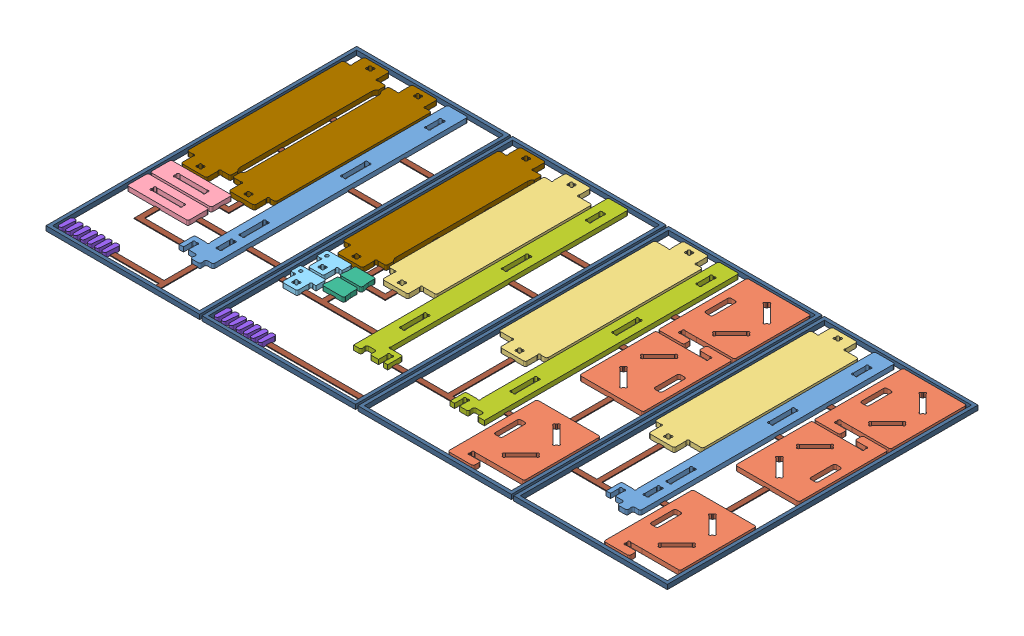
SolidWorks assembly growall_nest, configuration Défaut. Lengths in mm.
Overall size (2440 18 1220).
38 component instances, 11 part files, 87 mates.
Components (placement in the parent):
- post-2: post [Default] at (458.9899 18 -198) x (-1 0 0) z (0 -1 0) size (134 1025 18)
- shelf_side-1: shelf_side [Défaut] at (2418 0 -889) x (0 0 1) z (0 1 0) size (350 250 18)
- beam-1: beam [Défaut] at (1404.4949 0 -1198) x (-1 0 0) z (0 1 0) size (187.99 720 18)
- connector2-1: connector2 [Default] at (22 0 -469) x (0 0 1) z (0 1 0) size (82 240 18)
- connector3-1: connector3 [Défaut] at (654.25 0 -375) x (1 0 0) z (0 1 0) size (100 94 18)
- connector4-1: connector4 [Default] at (746.1933 0 -469) x (0 0 1) z (0 1 0) size (60 86.01 18)
- post2-1: post2 [Default] at (1009.7399 0 -198) x (1 0 0) z (0 1 0) size (134 1000 18)
- pin-16: pin [Défaut] at (29.8913 0 -29.8913) x (1 0 0) z (0 1 0) size (19.55 57.89 18)
- shelf_side-10: shelf_side [Défaut] at (1555.75 0 -848) x (0 0 -1) z (0 1 0) size (350 250 18)
- post2-2: post2 [Default] at (1523.4949 18 -198) x (-1 0 0) z (0 -1 0) size (134 1000 18)
- post-8: post [Default] at (2135.7449 18 -198) x (-1 0 0) z (0 -1 0) size (134 1025 18)
- connector2-2: connector2 [Default] at (22 0 -378) x (0 0 1) z (0 1 0) size (82 240 18)
- connector4-2: connector4 [Default] at (746.1933 0 -400) x (0 0 1) z (0 1 0) size (60 86.01 18)
- connector3-2: connector3 [Défaut] at (654.25 0 -272) x (1 0 0) z (0 1 0) size (100 94 18)
- shelf_side-11: shelf_side [Défaut] at (1555.75 0 -22) x (0 0 -1) z (0 1 0) size (350 250 18)
- shelf_side-12: shelf_side [Défaut] at (1805.75 0 -889) x (0 0 1) z (0 1 0) size (350 250 18)
- shelf_side-14: shelf_side [Défaut] at (2168 0 -22) x (0 0 -1) z (0 1 0) size (350 250 18)
- shelf_side-15: shelf_side [Défaut] at (2168 0 -848) x (0 0 -1) z (0 1 0) size (350 250 18)
- beam-4: beam [Défaut] at (1888.75 0 -478) x (1 0 0) z (0 1 0) size (187.99 720 18)
- beam2-3: beam2 [Défaut] at (239.9899 0 -478) x (1 0 0) z (0 1 0) size (169.49 720 18)
- beam2-4: beam2 [Défaut] at (152 0 -1198) x (-1 0 0) z (0 1 0) size (169.49 720 18)
- beam2-5: beam2 [Défaut] at (764.25 0 -1198) x (-1 0 0) z (0 1 0) size (169.49 720 18)
- layout-1: layout [Default] at origin size (2440 18 1220)
- pin-44: pin [Défaut] at (58.4394 0 -29.8913) x (1 0 0) z (0 1 0) size (19.55 57.89 18)
- pin-46: pin [Défaut] at (86.9874 0 -29.8913) x (1 0 0) z (0 1 0) size (19.55 57.89 18)
- pin-48: pin [Défaut] at (115.5355 0 -29.8913) x (1 0 0) z (0 1 0) size (19.55 57.89 18)
- pin-50: pin [Défaut] at (144.0835 0 -29.8913) x (1 0 0) z (0 1 0) size (19.55 57.89 18)
- pin-52: pin [Défaut] at (172.6316 0 -29.8913) x (1 0 0) z (0 1 0) size (19.55 57.89 18)
- pin-54: pin [Défaut] at (201.1797 0 -29.8913) x (1 0 0) z (0 1 0) size (19.55 57.89 18)
- beam-5: beam [Défaut] at (842.7449 0 -478) x (1 0 0) z (0 1 0) size (187.99 720 18)
- pin-55: pin [Défaut] at (642.1413 0 -29.8913) x (1 0 0) z (0 1 0) size (19.55 57.89 18)
- pin-56: pin [Défaut] at (670.6894 0 -29.8913) x (1 0 0) z (0 1 0) size (19.55 57.89 18)
- pin-57: pin [Défaut] at (699.2374 0 -29.8913) x (1 0 0) z (0 1 0) size (19.55 57.89 18)
- pin-58: pin [Défaut] at (727.7855 0 -29.8913) x (1 0 0) z (0 1 0) size (19.55 57.89 18)
- pin-59: pin [Défaut] at (756.3335 0 -29.8913) x (1 0 0) z (0 1 0) size (19.55 57.89 18)
- pin-60: pin [Défaut] at (784.8816 0 -29.8913) x (1 0 0) z (0 1 0) size (19.55 57.89 18)
- pin-61: pin [Défaut] at (813.4297 0 -29.8913) x (1 0 0) z (0 1 0) size (19.55 57.89 18)
- Tabs^growall_nest-1: Tabs^growall_nest [Défaut] at origin size (2414 3 1194) (virtual)
Mates (geometry in assembly coordinates):
- Coincident2: coordinate: point of ?
- Coincident3: coincident anti-aligned: plane of ? through (863.6224 0 -518.7909) normal (0 -1 0); plane of assembly through (0 0 0) normal (0 1 0)
- Coincident4: coincident anti-aligned: plane of beam2-3 through (244.9899 0 -523.2544) normal (0 -1 0); plane of assembly through (0 0 0) normal (0 1 0)
- Coincident5: coincident anti-aligned: plane of beam2-4 through (147 0 -1152.7456) normal (0 -1 0); plane of assembly through (0 0 0) normal (0 1 0)
- Coincident6: coincident anti-aligned: plane of beam2-5 through (759.25 0 -1152.7456) normal (0 -1 0); plane of assembly through (0 0 0) normal (0 1 0)
- Coincident7: coincident anti-aligned: plane of ? through (986.3675 0 -211) normal (0 -1 0); plane of assembly through (0 0 0) normal (0 1 0)
- Coincident8: coincident anti-aligned: plane of shelf_side-15 through (2168 0 -848) normal (0 -1 0); plane of assembly through (0 0 0) normal (0 1 0)
- Coincident9: coincident anti-aligned: plane of shelf_side-14 through (2168 0 -22) normal (0 -1 0); plane of assembly through (0 0 0) normal (0 1 0)
- Coincident10: coincident anti-aligned: plane of shelf_side-1 through (2418 0 -889) normal (0 -1 0); plane of assembly through (0 0 0) normal (0 1 0)
- Coincident11: coincident anti-aligned: plane of connector2-1 through (22 0 -469) normal (0 -1 0); plane of assembly through (0 0 0) normal (0 1 0)
- Coincident12: coincident anti-aligned: plane of connector4-1 through (746.1933 0 -469) normal (0 -1 0); plane of assembly through (0 0 0) normal (0 1 0)
- Coincident13: coincident anti-aligned: plane of connector3-1 through (656.75 0 -421.0122) normal (0 -1 0); plane of assembly through (0 0 0) normal (0 1 0)
- Coincident15: coincident aligned: plane of ? through (642.6717 0 233.5068) normal (0 1 0); plane of assembly through (0 0 0) normal (0 1 0)
- Coincident16: coincident anti-aligned: plane of post2-2 through (1448.4949 0 -266.7456) normal (0 -1 0); plane of assembly through (0 0 0) normal (0 1 0)
- Coincident17: coincident anti-aligned: plane of post-2 through (371.0021 0 -255.5) normal (0 -1 0); plane of assembly through (0 0 0) normal (0 1 0)
- Coincident18: coincident anti-aligned: plane of post2-1 through (1084.7399 0 -266.7456) normal (0 -1 0); plane of assembly through (0 0 0) normal (0 1 0)
- Coincident21: coincident aligned: plane of ? through (760.5544 0 227.5394) normal (0 1 0); plane of assembly through (0 0 0) normal (0 1 0)
- Coincident27: coincident anti-aligned: plane of ? through (1131.9971 0 248.5286) normal (0 -1 0); plane of assembly through (0 0 0) normal (0 1 0)
- Coincident28: coincident aligned: plane of ? through (572.6518 0 201.4453) normal (0 1 0); plane of assembly through (0 0 0) normal (0 1 0)
- Coincident29: coincident anti-aligned: plane of pin-16 through (29.8913 0 -29.8913) normal (0 -1 0); plane of assembly through (0 0 0) normal (0 1 0)
- Coincident30: coincident anti-aligned: plane of beam-4 through (1891.25 0 -524.0122) normal (0 -1 0); plane of assembly through (0 0 0) normal (0 1 0)
- Coincident31: coincident anti-aligned: plane of ? through (56.6175 0 980.4111) normal (0 -1 0); plane of assembly through (0 0 0) normal (0 1 0)
- Coincident32: coincident anti-aligned: plane of ? through (542.205 0 351.5889) normal (0 -1 0); plane of assembly through (0 0 0) normal (0 1 0)
- Coincident33: coincident anti-aligned: plane of beam-1 through (1401.9949 0 -1151.9878) normal (0 -1 0); plane of assembly through (0 0 0) normal (0 1 0)
- Coincident34: coincident anti-aligned: plane of shelf_side-10 through (1555.75 0 -848) normal (0 -1 0); plane of assembly through (0 0 0) normal (0 1 0)
- Coincident35: coincident anti-aligned: plane of shelf_side-11 through (1555.75 0 -22) normal (0 -1 0); plane of assembly through (0 0 0) normal (0 1 0)
- Coincident36: coincident anti-aligned: plane of shelf_side-12 through (1805.75 0 -889) normal (0 -1 0); plane of assembly through (0 0 0) normal (0 1 0)
- Coincident37: coincident anti-aligned: plane of ? through (224.8375 0 1224) normal (0 -1 0); plane of assembly through (0 0 0) normal (0 1 0)
- Coincident38: coincident anti-aligned: plane of connector3-2 through (656.75 0 -318.0122) normal (0 -1 0); plane of assembly through (0 0 0) normal (0 1 0)
- Coincident39: coincident anti-aligned: plane of connector2-2 through (22 0 -378) normal (0 -1 0); plane of assembly through (0 0 0) normal (0 1 0)
- Coincident40: coincident anti-aligned: plane of connector4-2 through (746.1933 0 -400) normal (0 -1 0); plane of assembly through (0 0 0) normal (0 1 0)
- Coincident42: coincident aligned: line of beam2-4 through (22 0 -1137) axis (0 0 1); line of layout-1 through (22 0 -1198) axis (0 0 1)
- Coincident43: coincident anti-aligned: line of beam2-4 through (145 0 -1198) axis (-1 0 0); line of layout-1 through (22 0 -1198) axis (1 0 0)
- Coincident50: coincident aligned: line of connector2-1 through (22 0 -462) axis (0 0 1); line of layout-1 through (22 0 -1198) axis (0 0 1)
- Coincident53: coincident aligned: line of connector2-2 through (22 0 -371) axis (0 0 1); line of layout-1 through (22 0 -1198) axis (0 0 1)
- Coincident58: coincident aligned: line of pin-16 through (22 0 -72.8913) axis (0 0 1); line of layout-1 through (22 0 -1198) axis (0 0 1)
- Coincident60: coincident aligned: line of beam2-5 through (634.25 0 -1137) axis (0 0 1); line of layout-1 through (634.25 0 -1198) axis (0 0 1)
- Coincident61: coincident anti-aligned: line of beam2-5 through (757.25 0 -1198) axis (-1 0 0); line of layout-1 through (634.25 0 -1198) axis (1 0 0)
- Coincident68: coincident aligned: line of ? through (636.3675 0 -454) axis (0 0 1); line of layout-1 through (636.3675 0 -1194) axis (0 0 1)
- Distance12: distance = 13 mm anti-aligned: plane of ? through (636.3675 18 -461) normal (0 0 -1); plane of beam2-5 through (766.3675 18 -474) normal (0 0 1)
- Coincident70: coincident aligned: line of connector3-2 through (634.25 0 -359) axis (0 0 1); line of layout-1 through (634.25 0 -1198) axis (0 0 1)
- Distance13: distance: line of connector4-2 through (743.25 0 -347.9251) axis (0 1 0); plane of connector3-2 through (734.25 18 -366) normal (1 0 0)
- Coincident74: coincident anti-aligned: line of beam-1 through (1246.5 0 -1137) axis (0 0 1); line of layout-1 through (1246.5 0 -22) axis (0 0 -1)
- Coincident75: coincident anti-aligned: line of beam-1 through (1397.4949 0 -1198) axis (-1 0 0); line of layout-1 through (1246.5 0 -1198) axis (1 0 0)
- Coincident88: coincident aligned: line of beam-4 through (1858.75 0 -1137) axis (0 0 1); line of layout-1 through (1858.75 0 -1198) axis (0 0 1)
- Coincident89: coincident aligned: line of beam-4 through (1895.75 0 -1198) axis (1 0 0); line of layout-1 through (1858.75 0 -1198) axis (1 0 0)
- Tangent1: tangent: cylinder of pin-16 through (29.8913 18 -29.8913) axis (0 -1 0) radius 7.8913; line of layout-1 through (22 0 -22) axis (1 0 0)
- Coincident100: coincident anti-aligned: line of shelf_side-15 through (2411 0 -1198) axis (-1 0 0); line of layout-1 through (1858.75 0 -1198) axis (1 0 0)
- Coincident101: coincident anti-aligned: line of shelf_side-15 through (2418 0 -905) axis (0 0 -1); line of layout-1 through (2418 0 -1198) axis (0 0 1)
- Coincident102: coincident anti-aligned: line of shelf_side-1 through (2418 0 -546) axis (0 0 -1); line of layout-1 through (2418 0 -1198) axis (0 0 1)
- Distance19: distance anti-aligned: plane of shelf_side-1 through (2318 18 -889) normal (0 0 -1); plane of shelf_side-15 through (2418 18 -898) normal (0 0 1)
- Coincident104: coincident anti-aligned: line of shelf_side-14 through (2418 0 -79) axis (0 0 -1); line of layout-1 through (2418 0 -1198) axis (0 0 1)
- Coincident105: coincident aligned: line of shelf_side-14 through (2175 0 -22) axis (1 0 0); line of layout-1 through (1858.75 0 -22) axis (1 0 0)
- Coincident106: coincident anti-aligned: line of shelf_side-10 through (1798.75 0 -1198) axis (-1 0 0); line of layout-1 through (1246.5 0 -1198) axis (1 0 0)
- Coincident107: coincident aligned: line of shelf_side-10 through (1805.75 0 -905) axis (0 0 -1); line of layout-1 through (1805.75 0 -22) axis (0 0 -1)
- Coincident108: coincident aligned: line of shelf_side-12 through (1805.75 0 -546) axis (0 0 -1); line of layout-1 through (1805.75 0 -22) axis (0 0 -1)
- Distance20: distance anti-aligned: plane of shelf_side-12 through (1705.75 18 -889) normal (0 0 -1); plane of shelf_side-10 through (1805.75 18 -898) normal (0 0 1)
- Coincident110: coincident aligned: line of shelf_side-11 through (1805.75 0 -79) axis (0 0 -1); line of layout-1 through (1805.75 0 -22) axis (0 0 -1)
- Coincident112: coincident aligned: line of shelf_side-11 through (1562.75 0 -22) axis (1 0 0); line of layout-1 through (1246.5 0 -22) axis (1 0 0)
- Coincident114: coincident anti-aligned: line of post2-2 through (1516.4949 0 -1198) axis (-1 0 0); line of layout-1 through (1246.5 0 -1198) axis (1 0 0)
- Distance23: distance anti-aligned: plane of post2-2 through (1443.4949 0 -266.7456) normal (-1 0 0); plane of beam-1 through (1434.4949 18 -838) normal (1 0 0)
- Coincident118: coincident anti-aligned: line of post-8 through (2128.7449 0 -1198) axis (-1 0 0); line of layout-1 through (1858.75 0 -1198) axis (1 0 0)
- Coincident119: coincident anti-aligned: plane of post-8 through (2047.7572 0 -255.5) normal (0 -1 0); plane of assembly through (0 0 0) normal (0 1 0)
- Distance25: distance anti-aligned: plane of post-8 through (2055.7449 0 -265.9878) normal (-1 0 0); plane of beam-4 through (2046.7449 18 -838) normal (1 0 0)
- Coincident122: coincident aligned: line of beam2-3 through (246.9899 0 -1198) axis (1 0 0); line of layout-1 through (22 0 -1198) axis (1 0 0)
- Distance27: distance = 13 mm anti-aligned: plane of beam2-5 through (805.8624 18 -1111.3239) normal (1 0 0); plane of ? through (818.8624 18 -1111.3239) normal (-1 0 0)
- Coincident125: coincident aligned: line of ? through (865.3574 0 -1194) axis (1 0 0); line of layout-1 through (636.3675 0 -1194) axis (1 0 0)
- Coïncidente1: coincident aligned: plane of beam2-5 through (759.25 0 -1152.7456) normal (0 -1 0); plane of beam-5 through (845.2449 0 -524.0122) normal (0 -1 0)
- Coïncidente3: coincident aligned: line of layout-1 through (634.25 0 -1198) axis (1 0 0); line of beam-5 through (849.7449 0 -1198) axis (1 0 0)
- Distance29: distance anti-aligned: plane of beam-5 through (812.7449 18 -838) normal (-1 0 0); plane of beam2-5 through (803.7449 18 -1115.2596) normal (1 0 0)
- Distance30: distance anti-aligned: plane of beam2-3 through (200.4949 18 -1115.2596) normal (-1 0 0); plane of beam2-4 through (191.4949 18 -1115.2596) normal (1 0 0)
- Distance31: distance anti-aligned: plane of beam2-4 through (152 18 -478) normal (0 0 1); plane of connector2-1 through (22 18 -469) normal (0 0 -1)
- Distance32: distance anti-aligned: plane of connector2-2 through (22 18 -378) normal (0 0 -1); plane of connector2-1 through (22 18 -387) normal (0 0 1)
- Distance34: distance anti-aligned: plane of post-2 through (378.9899 0 -265.9878) normal (-1 0 0); plane of beam2-3 through (369.9899 18 -838) normal (1 0 0)
- Coïncidente9: coincident anti-aligned: line of post-2 through (451.9899 0 -1198) axis (-1 0 0); line of layout-1 through (22 0 -1198) axis (1 0 0)
- Coïncidente11: coincident aligned: line of connector3-1 through (634.25 0 -462) axis (0 0 1); line of layout-1 through (634.25 0 -1198) axis (0 0 1)
- Distance36: distance anti-aligned: plane of connector3-1 through (634.25 18 -469) normal (0 0 -1); plane of beam2-5 through (764.25 18 -478) normal (0 0 1)
- Coïncidente13: coincident aligned: plane of connector3-1 through (634.25 18 -469) normal (0 0 -1); plane of connector4-1 through (826.1933 18 -469) normal (0 0 -1)
- Distance37: distance: line of connector4-1 through (743.25 0 -416.9251) axis (0 1 0); plane of connector3-1 through (734.25 18 -469) normal (1 0 0)
- Distance38: distance anti-aligned: plane of connector3-2 through (634.25 18 -366) normal (0 0 -1); plane of connector3-1 through (654.25 18 -375) normal (0 0 1)
- Distance40: distance anti-aligned: plane of connector4-2 through (826.1933 18 -400) normal (0 0 -1); plane of connector4-1 through (742.1933 18 -409) normal (0 0 1)
- Distance41: distance anti-aligned: plane of post2-1 through (1009.7399 18 -198) normal (-1 0 0); plane of beam-5 through (1000.7399 18 -838) normal (1 0 0)
- Coïncidente15: coincident aligned: line of post2-1 through (1016.7399 0 -1198) axis (1 0 0); line of layout-1 through (634.25 0 -1198) axis (1 0 0)
- Coïncidente16: coincident aligned: line of layout-1 through (634.25 0 -1198) axis (0 0 1); line of pin-55 through (634.25 0 -72.8913) axis (0 0 1)
- Coïncidente17: coincident anti-aligned: plane of pin-55 through (642.1413 0 -29.8913) normal (0 -1 0); plane of assembly through (0 0 0) normal (0 1 0)
- Tangent2: tangent: line of layout-1 through (634.25 0 -22) axis (1 0 0); cylinder of pin-55 through (642.1413 18 -29.8913) axis (0 -1 0) radius 7.8913
- Coïncidente19: coordinate: unknown of ?
